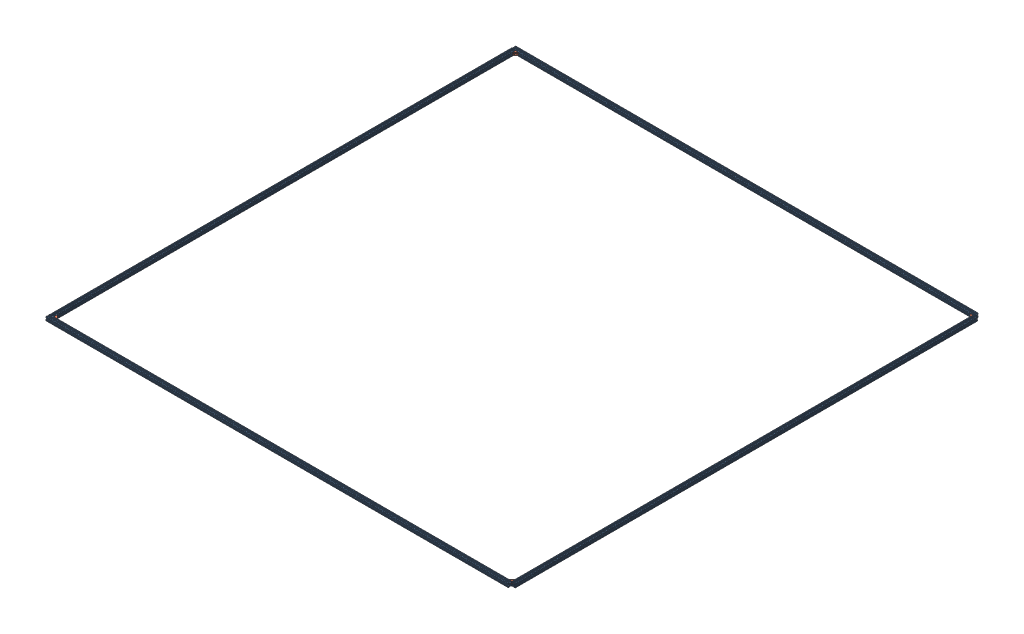
SolidWorks assembly Rack Level, configuration Default. Lengths in mm.
Overall size (3070.95 28.09 3097.47).
104 component instances, 2 part files, 18 mates.
Components (placement in the parent):
- big_connector_rod_24in-1: big_connector_rod_24in [Default] at origin size (25.4 25.4 3048)
  - connector_rod-1: connector_rod [Default] at (118.4239 27.3588 26.3342) size (25.4 25.4 127)
  - connector_rod-2: connector_rod [Default] at (118.4239 27.3588 -100.6658) size (25.4 25.4 127)
  - connector_rod-3: connector_rod [Default] at (118.4239 27.3588 -227.6658) size (25.4 25.4 127)
  - connector_rod-4: connector_rod [Default] at (118.4239 27.3588 -354.6658) size (25.4 25.4 127)
  - connector_rod-5: connector_rod [Default] at (118.4239 27.3588 153.3342) size (25.4 25.4 127)
  - connector_rod-6: connector_rod [Default] at (118.4239 27.3588 280.3342) size (25.4 25.4 127)
  - connector_rod-7: connector_rod [Default] at (118.4239 27.3588 407.3342) size (25.4 25.4 127)
  - connector_rod-8: connector_rod [Default] at (118.4239 27.3588 -481.6658) size (25.4 25.4 127)
  - connector_rod-9: connector_rod [Default] at (118.4239 27.3588 -608.6658) size (25.4 25.4 127)
  - connector_rod-10: connector_rod [Default] at (118.4239 27.3588 -862.6658) size (25.4 25.4 127)
  - connector_rod-11: connector_rod [Default] at (118.4239 27.3588 -735.6658) size (25.4 25.4 127)
  - connector_rod-12: connector_rod [Default] at (118.4239 27.3588 788.3342) size (25.4 25.4 127)
  - connector_rod-13: connector_rod [Default] at (118.4239 27.3588 534.3342) size (25.4 25.4 127)
  - connector_rod-14: connector_rod [Default] at (118.4239 27.3588 915.3342) x (-1 0 0) z (0 0 -1) size (25.4 25.4 127)
  - connector_rod-15: connector_rod [Default] at (118.4239 27.3588 915.3342) size (25.4 25.4 127)
  - connector_rod-16: connector_rod [Default] at (118.4239 27.3588 661.3342) size (25.4 25.4 127)
  - connector_rod-17: connector_rod [Default] at (118.4239 27.3588 1042.3342) x (-1 0 0) z (0 0 -1) size (25.4 25.4 127)
  - connector_rod-18: connector_rod [Default] at (118.4239 27.3588 1296.3342) size (25.4 25.4 127)
  - connector_rod-19: connector_rod [Default] at (118.4239 27.3588 -1116.6658) x (-1 0 0) z (0 0 -1) size (25.4 25.4 127)
  - connector_rod-20: connector_rod [Default] at (118.4239 27.3588 -1370.6658) x (-1 0 0) z (0 0 -1) size (25.4 25.4 127)
  - connector_rod-21: connector_rod [Default] at (118.4239 27.3588 1296.3342) x (-1 0 0) z (0 0 -1) size (25.4 25.4 127)
  - connector_rod-22: connector_rod [Default] at (118.4239 27.3588 -1243.6658) x (-1 0 0) z (0 0 -1) size (25.4 25.4 127)
  - connector_rod-23: connector_rod [Default] at (118.4239 27.3588 1423.3342) x (-1 0 0) z (0 0 -1) size (25.4 25.4 127)
  - connector_rod-24: connector_rod [Default] at (118.4239 27.3588 1550.3342) x (-1 0 0) z (0 0 -1) size (25.4 25.4 127)
- big_connector_rod_24in-5: big_connector_rod_24in [Default] at (1475.8697 0 1807.1242) x (0 0 -1) z (1 0 0) size (25.4 25.4 3048)
  - connector_rod-1: connector_rod [Default] at (118.4239 27.3588 26.3342) size (25.4 25.4 127)
  - connector_rod-2: connector_rod [Default] at (118.4239 27.3588 -100.6658) size (25.4 25.4 127)
  - connector_rod-3: connector_rod [Default] at (118.4239 27.3588 -227.6658) size (25.4 25.4 127)
  - connector_rod-4: connector_rod [Default] at (118.4239 27.3588 -354.6658) size (25.4 25.4 127)
  - connector_rod-5: connector_rod [Default] at (118.4239 27.3588 153.3342) size (25.4 25.4 127)
  - connector_rod-6: connector_rod [Default] at (118.4239 27.3588 280.3342) size (25.4 25.4 127)
  - connector_rod-7: connector_rod [Default] at (118.4239 27.3588 407.3342) size (25.4 25.4 127)
  - connector_rod-8: connector_rod [Default] at (118.4239 27.3588 -481.6658) size (25.4 25.4 127)
  - connector_rod-9: connector_rod [Default] at (118.4239 27.3588 -608.6658) size (25.4 25.4 127)
  - connector_rod-10: connector_rod [Default] at (118.4239 27.3588 -862.6658) size (25.4 25.4 127)
  - connector_rod-11: connector_rod [Default] at (118.4239 27.3588 -735.6658) size (25.4 25.4 127)
  - connector_rod-12: connector_rod [Default] at (118.4239 27.3588 788.3342) size (25.4 25.4 127)
  - connector_rod-13: connector_rod [Default] at (118.4239 27.3588 534.3342) size (25.4 25.4 127)
  - connector_rod-14: connector_rod [Default] at (118.4239 27.3588 915.3342) x (-1 0 0) z (0 0 -1) size (25.4 25.4 127)
  - connector_rod-15: connector_rod [Default] at (118.4239 27.3588 915.3342) size (25.4 25.4 127)
  - connector_rod-16: connector_rod [Default] at (118.4239 27.3588 661.3342) size (25.4 25.4 127)
  - connector_rod-17: connector_rod [Default] at (118.4239 27.3588 1042.3342) x (-1 0 0) z (0 0 -1) size (25.4 25.4 127)
  - connector_rod-18: connector_rod [Default] at (118.4239 27.3588 1296.3342) size (25.4 25.4 127)
  - connector_rod-19: connector_rod [Default] at (118.4239 27.3588 -1116.6658) x (-1 0 0) z (0 0 -1) size (25.4 25.4 127)
  - connector_rod-20: connector_rod [Default] at (118.4239 27.3588 -1370.6658) x (-1 0 0) z (0 0 -1) size (25.4 25.4 127)
  - connector_rod-21: connector_rod [Default] at (118.4239 27.3588 1296.3342) x (-1 0 0) z (0 0 -1) size (25.4 25.4 127)
  - connector_rod-22: connector_rod [Default] at (118.4239 27.3588 -1243.6658) x (-1 0 0) z (0 0 -1) size (25.4 25.4 127)
  - connector_rod-23: connector_rod [Default] at (118.4239 27.3588 1423.3342) x (-1 0 0) z (0 0 -1) size (25.4 25.4 127)
  - connector_rod-24: connector_rod [Default] at (118.4239 27.3588 1550.3342) x (-1 0 0) z (0 0 -1) size (25.4 25.4 127)
- big_connector_rod_24in-6: big_connector_rod_24in [Default] at (3045.03 -2.6868 -1.1586) size (25.4 25.4 3048)
  - connector_rod-1: connector_rod [Default] at (118.4239 27.3588 26.3342) size (25.4 25.4 127)
  - connector_rod-2: connector_rod [Default] at (118.4239 27.3588 -100.6658) size (25.4 25.4 127)
  - connector_rod-3: connector_rod [Default] at (118.4239 27.3588 -227.6658) size (25.4 25.4 127)
  - connector_rod-4: connector_rod [Default] at (118.4239 27.3588 -354.6658) size (25.4 25.4 127)
  - connector_rod-5: connector_rod [Default] at (118.4239 27.3588 153.3342) size (25.4 25.4 127)
  - connector_rod-6: connector_rod [Default] at (118.4239 27.3588 280.3342) size (25.4 25.4 127)
  - connector_rod-7: connector_rod [Default] at (118.4239 27.3588 407.3342) size (25.4 25.4 127)
  - connector_rod-8: connector_rod [Default] at (118.4239 27.3588 -481.6658) size (25.4 25.4 127)
  - connector_rod-9: connector_rod [Default] at (118.4239 27.3588 -608.6658) size (25.4 25.4 127)
  - connector_rod-10: connector_rod [Default] at (118.4239 27.3588 -862.6658) size (25.4 25.4 127)
  - connector_rod-11: connector_rod [Default] at (118.4239 27.3588 -735.6658) size (25.4 25.4 127)
  - connector_rod-12: connector_rod [Default] at (118.4239 27.3588 788.3342) size (25.4 25.4 127)
  - connector_rod-13: connector_rod [Default] at (118.4239 27.3588 534.3342) size (25.4 25.4 127)
  - connector_rod-14: connector_rod [Default] at (118.4239 27.3588 915.3342) x (-1 0 0) z (0 0 -1) size (25.4 25.4 127)
  - connector_rod-15: connector_rod [Default] at (118.4239 27.3588 915.3342) size (25.4 25.4 127)
  - connector_rod-16: connector_rod [Default] at (118.4239 27.3588 661.3342) size (25.4 25.4 127)
  - connector_rod-17: connector_rod [Default] at (118.4239 27.3588 1042.3342) x (-1 0 0) z (0 0 -1) size (25.4 25.4 127)
  - connector_rod-18: connector_rod [Default] at (118.4239 27.3588 1296.3342) size (25.4 25.4 127)
  - connector_rod-19: connector_rod [Default] at (118.4239 27.3588 -1116.6658) x (-1 0 0) z (0 0 -1) size (25.4 25.4 127)
  - connector_rod-20: connector_rod [Default] at (118.4239 27.3588 -1370.6658) x (-1 0 0) z (0 0 -1) size (25.4 25.4 127)
  - connector_rod-21: connector_rod [Default] at (118.4239 27.3588 1296.3342) x (-1 0 0) z (0 0 -1) size (25.4 25.4 127)
  - connector_rod-22: connector_rod [Default] at (118.4239 27.3588 -1243.6658) x (-1 0 0) z (0 0 -1) size (25.4 25.4 127)
  - connector_rod-23: connector_rod [Default] at (118.4239 27.3588 1423.3342) x (-1 0 0) z (0 0 -1) size (25.4 25.4 127)
  - connector_rod-24: connector_rod [Default] at (118.4239 27.3588 1550.3342) x (-1 0 0) z (0 0 -1) size (25.4 25.4 127)
- big_connector_rod_24in-7: big_connector_rod_24in [Default] at (1477.9148 -2.6868 -1264.9419) x (0 0 -1) z (1 0 0) size (25.4 25.4 3048)
  - connector_rod-1: connector_rod [Default] at (118.4239 27.3588 26.3342) size (25.4 25.4 127)
  - connector_rod-2: connector_rod [Default] at (118.4239 27.3588 -100.6658) size (25.4 25.4 127)
  - connector_rod-3: connector_rod [Default] at (118.4239 27.3588 -227.6658) size (25.4 25.4 127)
  - connector_rod-4: connector_rod [Default] at (118.4239 27.3588 -354.6658) size (25.4 25.4 127)
  - connector_rod-5: connector_rod [Default] at (118.4239 27.3588 153.3342) size (25.4 25.4 127)
  - connector_rod-6: connector_rod [Default] at (118.4239 27.3588 280.3342) size (25.4 25.4 127)
  - connector_rod-7: connector_rod [Default] at (118.4239 27.3588 407.3342) size (25.4 25.4 127)
  - connector_rod-8: connector_rod [Default] at (118.4239 27.3588 -481.6658) size (25.4 25.4 127)
  - connector_rod-9: connector_rod [Default] at (118.4239 27.3588 -608.6658) size (25.4 25.4 127)
  - connector_rod-10: connector_rod [Default] at (118.4239 27.3588 -862.6658) size (25.4 25.4 127)
  - connector_rod-11: connector_rod [Default] at (118.4239 27.3588 -735.6658) size (25.4 25.4 127)
  - connector_rod-12: connector_rod [Default] at (118.4239 27.3588 788.3342) size (25.4 25.4 127)
  - connector_rod-13: connector_rod [Default] at (118.4239 27.3588 534.3342) size (25.4 25.4 127)
  - connector_rod-14: connector_rod [Default] at (118.4239 27.3588 915.3342) x (-1 0 0) z (0 0 -1) size (25.4 25.4 127)
  - connector_rod-15: connector_rod [Default] at (118.4239 27.3588 915.3342) size (25.4 25.4 127)
  - connector_rod-16: connector_rod [Default] at (118.4239 27.3588 661.3342) size (25.4 25.4 127)
  - connector_rod-17: connector_rod [Default] at (118.4239 27.3588 1042.3342) x (-1 0 0) z (0 0 -1) size (25.4 25.4 127)
  - connector_rod-18: connector_rod [Default] at (118.4239 27.3588 1296.3342) size (25.4 25.4 127)
  - connector_rod-19: connector_rod [Default] at (118.4239 27.3588 -1116.6658) x (-1 0 0) z (0 0 -1) size (25.4 25.4 127)
  - connector_rod-20: connector_rod [Default] at (118.4239 27.3588 -1370.6658) x (-1 0 0) z (0 0 -1) size (25.4 25.4 127)
  - connector_rod-21: connector_rod [Default] at (118.4239 27.3588 1296.3342) x (-1 0 0) z (0 0 -1) size (25.4 25.4 127)
  - connector_rod-22: connector_rod [Default] at (118.4239 27.3588 -1243.6658) x (-1 0 0) z (0 0 -1) size (25.4 25.4 127)
  - connector_rod-23: connector_rod [Default] at (118.4239 27.3588 1423.3342) x (-1 0 0) z (0 0 -1) size (25.4 25.4 127)
  - connector_rod-24: connector_rod [Default] at (118.4239 27.3588 1550.3342) x (-1 0 0) z (0 0 -1) size (25.4 25.4 127)
- corner_bracket-1: corner_bracket [Default] at (131.1239 27.1203 -1370.6658) x (0 -1 0) z (0 0 1) size (17 21.5 21.5)
- corner_bracket-2: corner_bracket [Default] at (131.1239 29.8071 1676.0002) x (0 1 0) z (0 0 -1) size (17 21.5 21.5)
- corner_bracket-3: corner_bracket [Default] at (3150.7539 24.4335 -1370.6658) x (0 1 0) z (0 0 1) size (17 21.5 21.5)
- corner_bracket-4: corner_bracket [Default] at (3150.7539 27.5973 1676.0002) x (0 1 0) z (-1 0 0) size (17 21.5 21.5)
Mates (geometry in assembly coordinates):
- Coincident1: coincident anti-aligned: plane of big_connector_rod_24in-1/connector_rod-20 through (131.1239 36.9092 -1243.6658) normal (1 0 0); plane of corner_bracket-1 through (131.1239 18.6203 -1350.6658) normal (-1 0 0)
- Tangent1: tangent anti-aligned: cylinder of big_connector_rod_24in-1/connector_rod-20 through (130.019 23.0154 -1243.6658) axis (0 0 -1) radius 1.1049; plane of corner_bracket-1 through (131.1239 24.1203 -1370.6658) normal (0 -1 0)
- Coincident2: coincident aligned: plane of big_connector_rod_24in-1/connector_rod-20 through (131.1239 17.3004 -1370.6658) normal (0 0 -1); plane of corner_bracket-1 through (131.1239 18.6203 -1370.6658) normal (0 0 -1)
- Coincident3: coincident anti-aligned: plane of big_connector_rod_24in-7/connector_rod-20 through (234.249 15.1216 -1370.6658) normal (0 0 1); plane of corner_bracket-1 through (131.1239 18.6203 -1370.6658) normal (0 0 -1)
- Tangent2: tangent aligned: cylinder of big_connector_rod_24in-7/connector_rod-20 through (234.249 29.0154 -1371.7707) axis (-1 0 0) radius 1.1049; plane of corner_bracket-1 through (131.1239 30.1203 -1370.6658) normal (0 1 0)
- Tangent3: tangent aligned: cylinder of big_connector_rod_24in-7/connector_rod-20 through (234.249 29.0154 -1371.7707) axis (-1 0 0) radius 1.1049; plane of corner_bracket-1 through (131.1239 30.1203 -1370.6658) normal (0 1 0)
- Coincident7: coincident anti-aligned: plane of big_connector_rod_24in-5/connector_rod-20 through (232.2039 36.9092 1676.0002) normal (0 0 -1); plane of corner_bracket-2 through (131.1239 38.3071 1676.0002) normal (0 0 1)
- Tangent5: tangent aligned: cylinder of big_connector_rod_24in-5/connector_rod-20 through (232.2039 31.7022 1677.1051) axis (-1 0 0) radius 1.1049; plane of corner_bracket-2 through (131.1239 32.8071 1676.0002) normal (0 1 0)
- Coincident9: coincident anti-aligned: plane of big_connector_rod_24in-1/connector_rod-24 through (131.1239 36.9092 1677.3342) normal (1 0 0); plane of corner_bracket-2 through (131.1239 38.3071 1656.0002) normal (-1 0 0)
- Tangent6: tangent aligned: cylinder of big_connector_rod_24in-1/connector_rod-24 through (130.019 31.7022 1677.3342) axis (0 0 -1) radius 1.1049; plane of corner_bracket-2 through (131.1239 32.8071 1676.0002) normal (0 1 0)
- Coincident11: coincident anti-aligned: plane of big_connector_rod_24in-7/connector_rod-24 through (3155.249 31.0051 -1370.6658) normal (0 0 1); plane of corner_bracket-3 through (3150.7539 32.9335 -1370.6658) normal (0 0 -1)
- Coincident12: coincident anti-aligned: plane of big_connector_rod_24in-7/connector_rod-24 through (3155.249 31.0051 -1370.6658) normal (0 0 1); plane of corner_bracket-3 through (3150.7539 32.9335 -1370.6658) normal (0 0 -1)
- Tangent8: tangent anti-aligned: cylinder of big_connector_rod_24in-7/connector_rod-24 through (3155.249 20.3286 -1371.7707) axis (-1 0 0) radius 1.1049; plane of corner_bracket-3 through (3150.7539 21.4335 -1370.6658) normal (0 -1 0)
- Coincident13: coincident anti-aligned: plane of big_connector_rod_24in-6/connector_rod-20 through (3150.7539 31.0051 -1244.8244) normal (-1 0 0); plane of corner_bracket-3 through (3150.7539 32.9335 -1350.6658) normal (1 0 0)
- Tangent9: tangent anti-aligned: cylinder of big_connector_rod_24in-6/connector_rod-20 through (3151.8588 20.3286 -1244.8244) axis (0 0 -1) radius 1.1049; plane of corner_bracket-3 through (3150.7539 21.4335 -1370.6658) normal (0 -1 0)
- Coincident14: coincident anti-aligned: plane of big_connector_rod_24in-5/connector_rod-24 through (3153.2039 21.0258 1676.0002) normal (0 0 -1); plane of corner_bracket-4 through (3130.7539 36.0973 1676.0002) normal (0 0 1)
- Tangent10: tangent anti-aligned: cylinder of big_connector_rod_24in-5/connector_rod-24 through (3153.2039 31.7022 1677.1051) axis (-1 0 0) radius 1.1049; plane of corner_bracket-4 through (3150.7539 30.5973 1676.0002) normal (0 1 0)
- Coincident15: coincident anti-aligned: plane of big_connector_rod_24in-6/connector_rod-24 through (3150.7539 31.0051 1676.1756) normal (-1 0 0); plane of corner_bracket-4 through (3150.7539 36.0973 1676.0002) normal (1 0 0)
